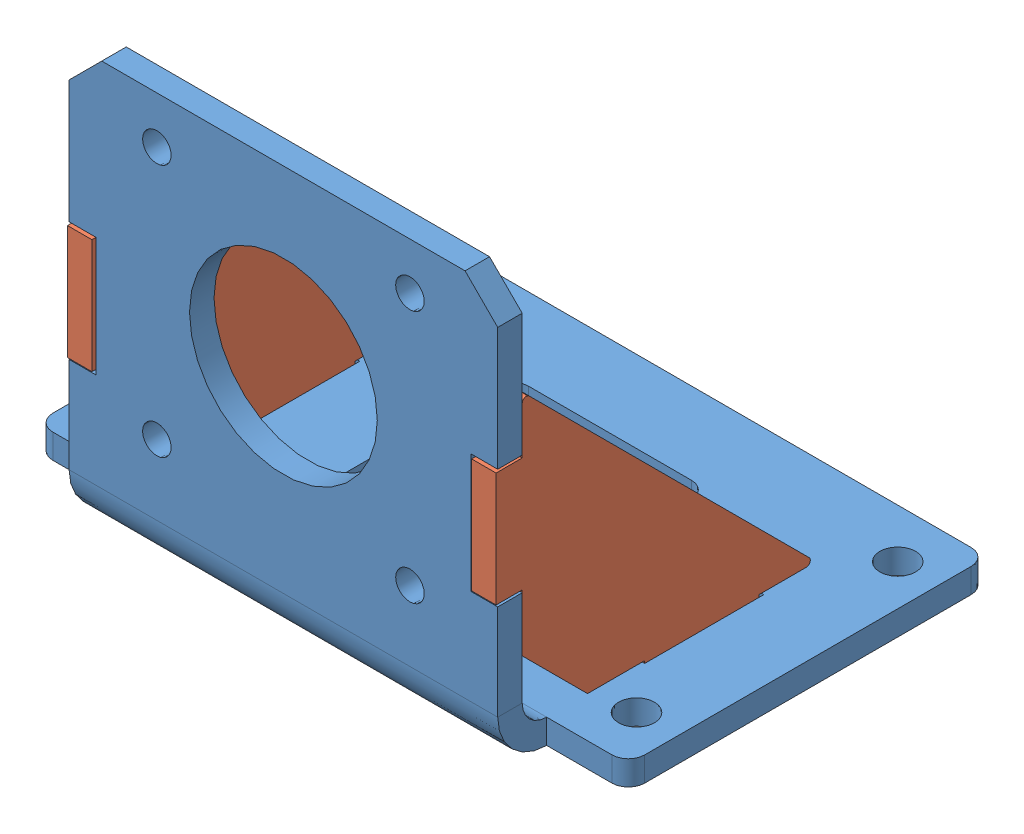
SolidWorks assembly NEMA_17_stand_welded, configuration Default. Lengths in mm.
Overall size (72.5 51.55 50.2).
3 component instances, 2 part files, 9 mates.
Components (placement in the parent):
- NEMA_17_stand_01-1: NEMA_17_stand_01 [Default] at (0 30.1 0) size (72.5 51.35 50)
- Planka_01-1: Planka_01 [Default] at (-23.25 3 0) x (0 0 -1) z (1 0 0) size (38.49 38.49 3)
- Planka_01-2: Planka_01 [Default] at (26.25 3 0) x (0 0 -1) z (1 0 0) size (38.49 38.49 3)
Mates (geometry in assembly coordinates):
- Coincident94: coincident: plane of assembly; plane of assembly; plane of NEMA_17_stand_01-1 through (0 3 0) normal (0 1 0); plane of Planka_01-1 through (-26.25 3 -36) normal (0 -1 0)
- Coincident95: coincident: plane of assembly; plane of assembly; plane of NEMA_17_stand_01-1 through (0 30.1 0) normal (0 0 -1); plane of Planka_01-1 through (-26.25 11 0) normal (0 0 1)
- Coincident96: coincident: plane of assembly; plane of NEMA_17_stand_01-1 through (-26.25 8.85 3) normal (-1 0 0); plane of Planka_01-1 through (-26.25 3 0) normal (-1 0 0)
- Coincident97: coincident: plane of assembly; plane of assembly; plane of NEMA_17_stand_01-1 through (0 3 0) normal (0 1 0); plane of Planka_01-2 through (23.25 3 -36) normal (0 -1 0)
- Coincident98: coincident: plane of assembly; plane of NEMA_17_stand_01-1 through (26.25 8.85 3) normal (1 0 0); plane of Planka_01-2 through (26.25 3 0) normal (1 0 0)
- Coincident99: coincident: plane of assembly; plane of assembly; plane of NEMA_17_stand_01-1 through (0 30.1 0) normal (0 0 -1); plane of Planka_01-2 through (23.25 11 0) normal (0 0 1)
- Coincident100: coincident: plane of assembly through (0 0 0) normal (0 1 0); plane of NEMA_17_stand_01-1 through (0 0 0) normal (0 -1 0); plane of assembly
- Coincident101: coincident: plane of assembly through (0 0 0) normal (0 0 1); plane of NEMA_17_stand_01-1 through (0 30.1 0) normal (0 0 1); plane of assembly
- Coincident102: coincident: plane of assembly through (0 0 0) normal (1 0 0); plane of NEMA_17_stand_01-1 through (0 30.1 0) normal (1 0 0); plane of assembly
